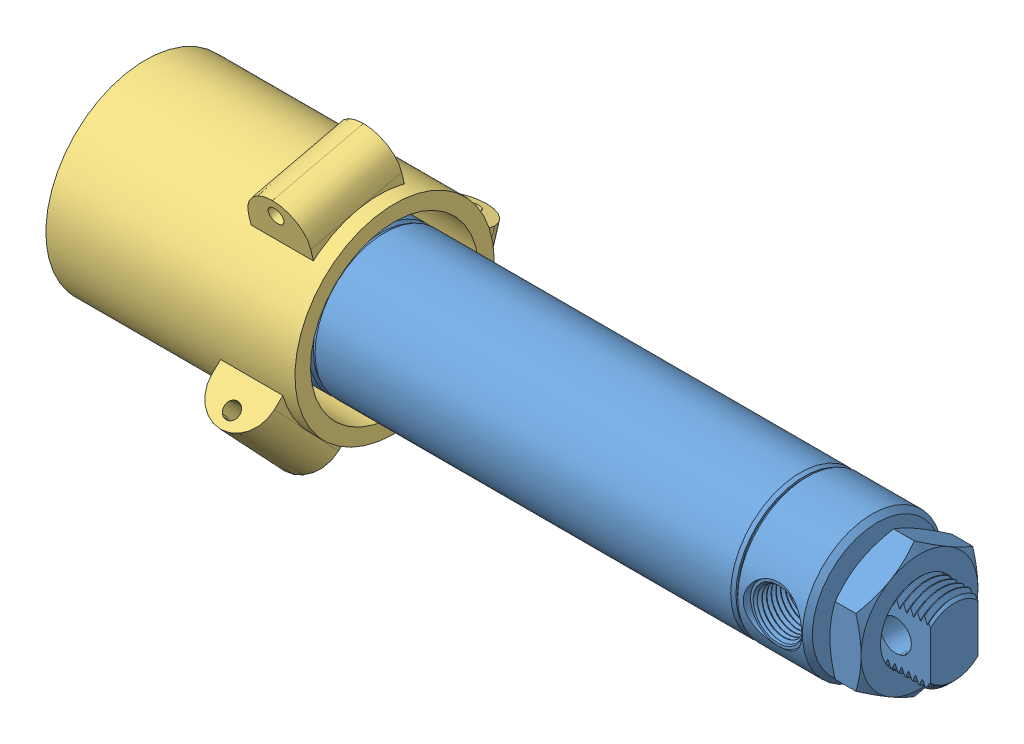
SolidWorks assembly Piston Assem, configuration Default. Lengths in mm.
Overall size (168.77 73.65 73.32).
3 component instances, 3 part files, 4 mates.
Components (placement in the parent):
- Piston Body-1: Piston Body [6498K654] at (48.3607 91.1672 114.2196) size (153.11 28.45 28.45)
- Piston Shaft-1: Piston Shaft [6498K654] at (48.3607 91.1672 114.2196) x (1 0 0) z (0 -0.982174 -0.187974) size (70.22 8.18 8.17)
- Piston Cup CORRECT-2: Piston Cup CORRECT [Default] at (-32.5383 91.1672 114.2196) x (0 -0.728683 -0.684851) z (0 -0.684851 0.728683) size (55.72 50.8 48.25)
Mates (geometry in assembly coordinates):
- Concentric1: concentric: circle of Piston Body-1; cylinder of Piston Shaft-1 through (-23.0133 91.1672 114.2196) axis (-1 0 0) radius 3.9624
- LimitDistance1: limit distance = 15.748 mm: plane of Piston Body-1 through (-19.9653 91.1672 114.2196) normal (-1 0 0); plane of Piston Shaft-1 through (-35.7133 91.9133 110.3216) normal (-1 0 0)
- Concentric4: concentric: circle of Piston Shaft-1; circle of Piston Cup CORRECT-2
- Distance1: distance = 3.175 mm: plane of Piston Cup CORRECT-2 through (-32.5383 91.1672 114.2196) normal (-1 0 0); plane of Piston Shaft-1 through (-35.7133 91.9133 110.3216) normal (-1 0 0)
